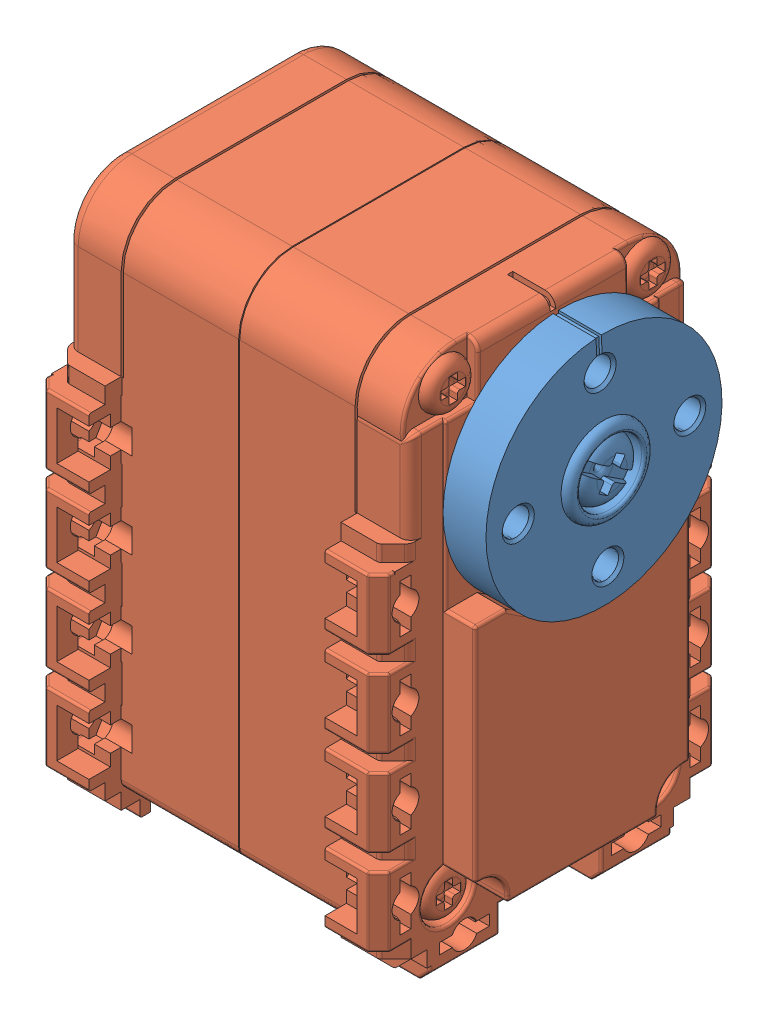
SolidWorks assembly AX12, configuration Default. Lengths in mm.
Overall size (40.85 50 32).
3 component instances, 3 part files, 0 mates.
Components (placement in the parent):
- ax12_wheel-1: ax12_wheel [Default] at (17.5 16.25 0.5) x (0 0.99898 0.045152) z (0 0.045152 -0.99898) size (22 14.85 22)
- ax12_box-1: ax12_box [Default] at (-1.5 4.25 0.5) x (0 -1 0) z (0 0 -1) size (50 38.01 32)
- ax12_cog-1: ax12_cog [Default] at origin size (1 1 1)
